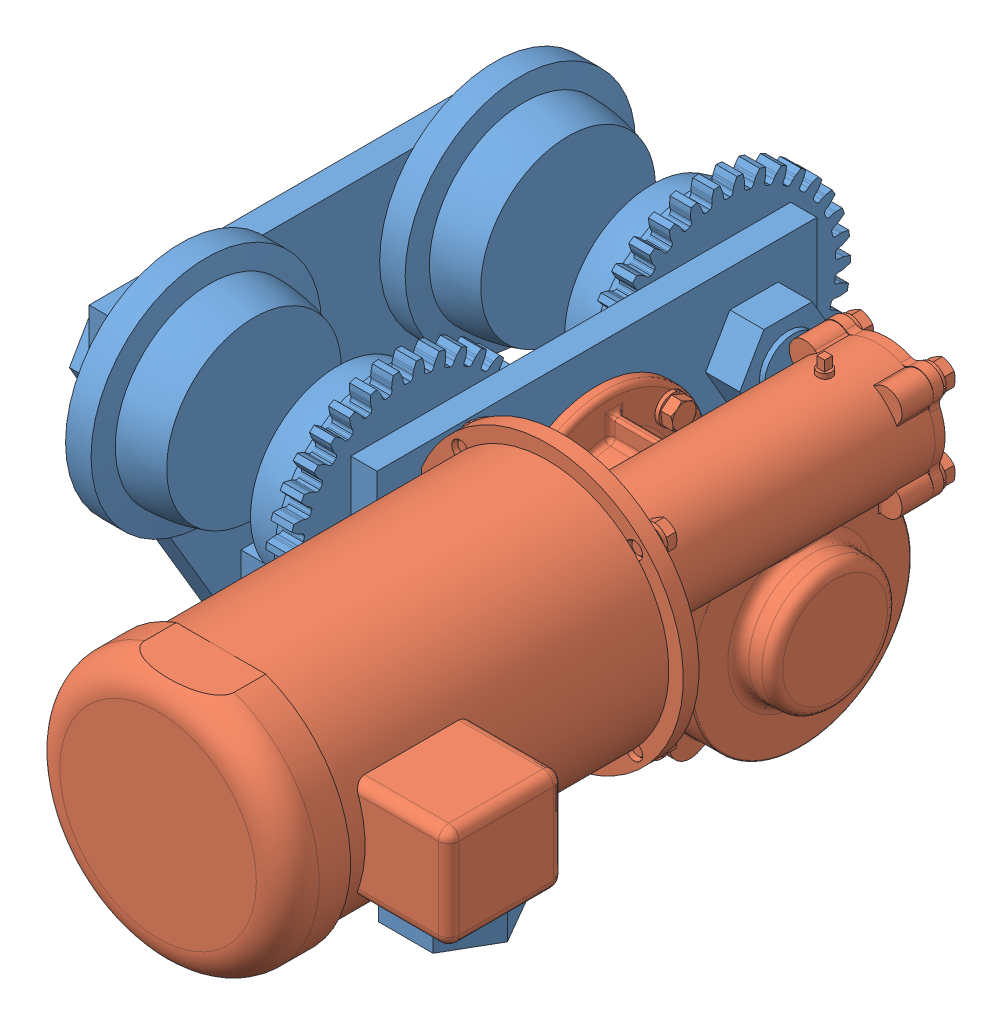
SolidWorks assembly M2631B-LH, configuration Default. Lengths in mm.
Overall size (426.15 413.65 540.72).
2 component instances, 2 part files, 3 mates.
Components (placement in the parent):
- Copy of M2631B-TROLLEY- SECTION^M2631B-LH-1: Copy of M2631B-TROLLEY- SECTION^M2631B-LH [S8x18.4#] at origin size (222.38 375.83 342.81) (virtual)
- Copy of SDT GEAR REDUCER LH^M2631B-LH-1: Copy of SDT GEAR REDUCER LH^M2631B-LH [Default] at (190.5 120.2538 0) x (-1 0 0) z (0 0 -1) size (229.23 225.42 451.54) (virtual)
Mates (geometry in assembly coordinates):
- Coincident1: coincident aligned: plane of Copy of M2631B-TROLLEY- SECTION^M2631B-LH-1 through (0 120.2538 0) normal (0 1 0); plane of Copy of SDT GEAR REDUCER LH^M2631B-LH-1
- Coincident2: coincident anti-aligned: plane of Copy of M2631B-TROLLEY- SECTION^M2631B-LH-1 through (0 0 0) normal (0 0 1); plane of Copy of SDT GEAR REDUCER LH^M2631B-LH-1 through (190.5 120.2538 0) normal (0 0 -1)
- Distance1: distance = 14.2875 mm aligned: plane of Copy of M2631B-TROLLEY- SECTION^M2631B-LH-1 through (71.4375 0 -133.35) normal (-1 0 0); plane of Copy of SDT GEAR REDUCER LH^M2631B-LH-1 through (85.725 120.2538 0) normal (-1 0 0)
